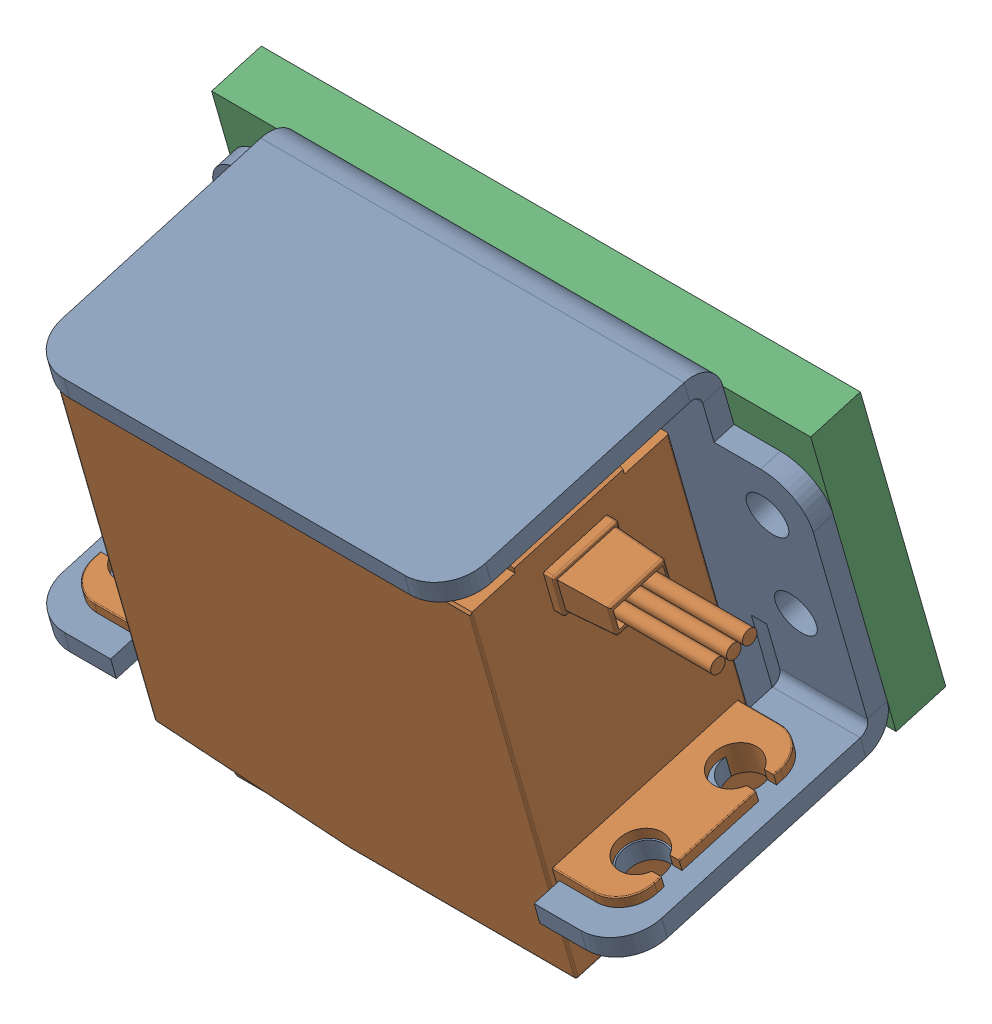
SolidWorks assembly Servomountassemblywithplate, configuration Default. Lengths in mm.
Overall size (63.92 53.06 39.89).
3 component instances, 3 part files, 4 mates.
Components (placement in the parent):
- BRACKET-1: BRACKET [Défaut] at (23.7908 -34.1386 -116.3619) x (1 0 0) z (0 -0.961262 -0.275637) size (58 27 37.5)
- SERVO-1: SERVO [Default] at (23.6864 -61.5912 -98.1352) x (0.001333 0.275637 -0.961261) z (-0.999999 0.000368 -0.001282) size (20 46.03 62.2)
- plate-1: plate [Default] at (52.7908 -64.607 -130.3001) x (1 0 0) z (0 -0.275637 0.961262) size (58 30 5)
Mates (geometry in assembly coordinates):
- Concentric5: concentric anti-aligned: cylinder of BRACKET-1 through (48.0408 -71.3371 -106.3576) axis (0 -0.961262 -0.275637) radius 2; circle of SERVO-1
- Lock1: lock: unknown of BRACKET-1; unknown of SERVO-1
- Coincident2: coincident anti-aligned: circle of BRACKET-1; cylinder of plate-1 through (-0.4592 -45.7987 -119.7054) axis (0 0.275637 -0.961262) radius 2
- Coincident3: coincident aligned: circle of BRACKET-1; circle of plate-1
